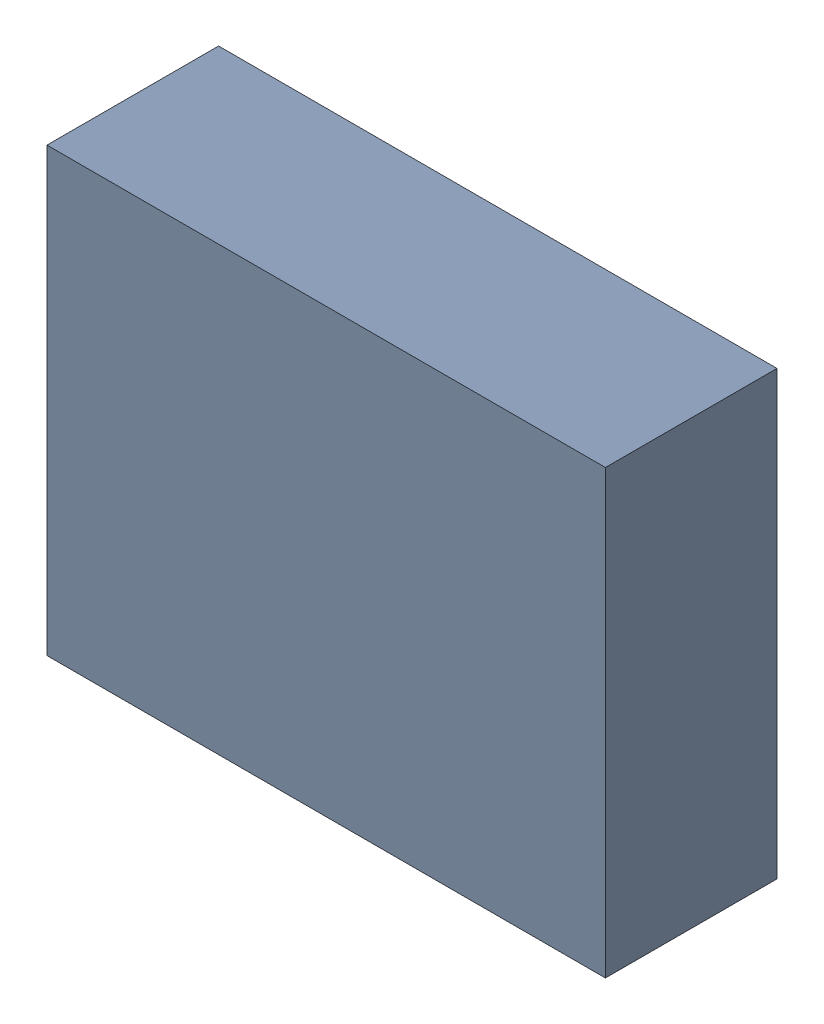
SolidWorks assembly OP4, configuration Default. Lengths in mm.
Overall size (5.04 3.99 1.55).
2 component instances, 1 part files, 0 mates.
Components (placement in the parent):
- 407985952-1: 407985952 [Default] at (35.814 60.198 0.2157) size (5.04 3.99 1.55)
  - Extruded-1: Extruded [Default] at origin size (5.04 3.99 1.55)
